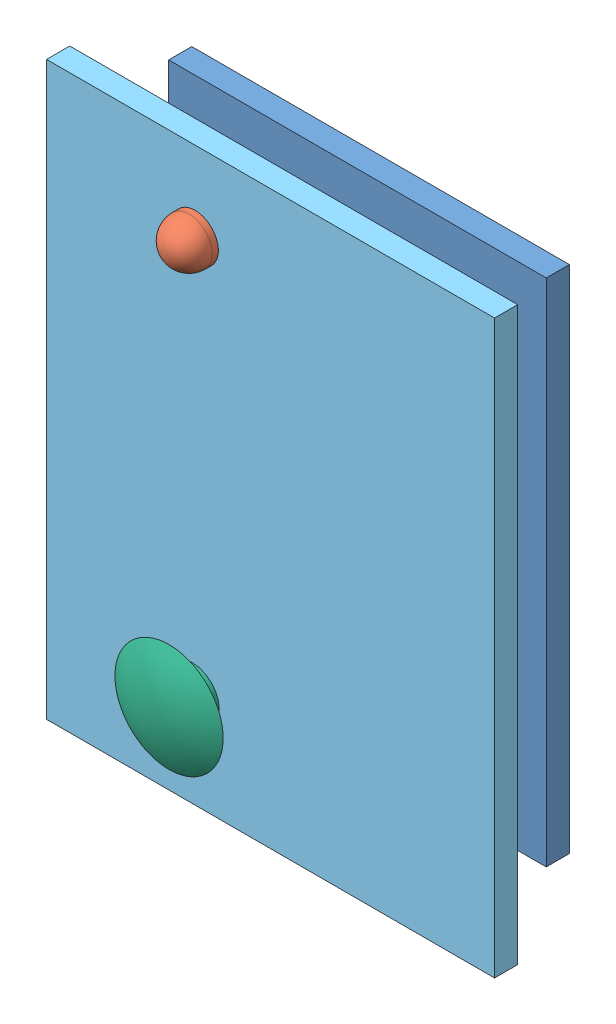
SolidWorks assembly Установка на панель, configuration По умолчанию. Lengths in mm.
Overall size (29 37 10.9).
7 component instances, 6 part files, 11 mates.
Components (placement in the parent):
- Плата-2: Плата [По умолчанию] at (-19.3757 14.8386 11.1863) size (24.45 33.02 1.6)
- Светодиод White-1: Светодиод White [По умолчанию] at (-11.7557 44.6836 15.4863) x (0 0 -1) z (1 0 0) size (15 4 3.6)
- Кнопка-1: Кнопка [По умолчанию] at (-11.9466 18.9926 12.8863) x (1 0 0) z (0 -1 0) size (8 3.1 6.3)
  - B3FS_1000_BASE-1: B3FS_1000_BASE [По умолчанию] at origin size (8 2.6 6.3)
  - B3FS_1000_BUTTON-1: B3FS_1000_BUTTON [По умолчанию] at (0 3 0) x (0.711738 0 -0.702446) z (0.702446 0 0.711738) size (3 0.6 3)
- Панель-1: Панель [По умолчанию] at (-21.3757 12.8386 17.0863) size (29 37 1.5)
- Кнопка-2: Кнопка [По умолчанию] at (1.2262 2.3103 54.0176) x (0 0 1) z (-0.995928 -0.090149 0) size (5 7 7)
Mates (geometry in assembly coordinates):
- Концентричный1: concentric anti-aligned: cylinder of Светодиод White-1 through (-11.7557 44.6836 15.4863) axis (0 0 -1) radius 1.5; cylinder of Панель-1 through (-11.7557 44.6836 17.0863) axis (0 0 1) radius 1.5
- Концентричный3: concentric aligned: cylinder of Панель-1 through (-11.9466 18.9926 17.0863) axis (0 0 1) radius 1.75; circle of Кнопка-2
- Расстояние1: distance = 0.5 mm aligned: plane of Кнопка-2; plane of Панель-1 through (-21.3757 12.8386 18.5863) normal (0 0 1)
- Совпадение5: coincident anti-aligned: plane of Плата-2 through (-19.3757 14.8386 12.7863) normal (0 0 1); plane of Кнопка-1/B3FS_1000_BASE-1 through (-15.1466 20.8926 12.7863) normal (0 0 -1)
- Расстояние4: distance = 0.35 mm aligned: plane of Кнопка-1/B3FS_1000_BASE-1 through (-15.4466 16.3926 13.7863) normal (0 -1 0); plane of Плата-2 through (-16.7468 16.0426 12.7863) normal (0 -1 0)
- Совпадение6: coincident aligned: plane of Плата-2 through (-15.1466 17.4447 12.7863) normal (1 0 0); plane of Кнопка-1/B3FS_1000_BASE-1 through (-15.1466 17.0926 13.4863) normal (1 0 0)
- Параллельность3: parallel aligned: plane of Плата-2 through (-19.3757 47.8586 12.6863) normal (0 1 0); plane of Светодиод White-1 through (-12.7257 44.9336 5.4863) normal (0 1 0)
- Расстояние5: distance = 4.4 mm anti-aligned: plane of Плата-2 through (-19.3757 14.8386 12.6863) normal (0 0 1); plane of Панель-1 through (-21.3757 12.8386 17.0863) normal (0 0 -1)
- Расстояние6: distance = 2.8 mm anti-aligned: plane of Плата-2 through (-19.3757 14.8386 12.6863) normal (0 0 1); plane of Светодиод White-1 through (-11.7557 44.6836 15.4863) normal (0 0 -1)
- Расстояние7: distance = 2 mm aligned: plane of Панель-1 through (-21.3757 12.8386 18.5863) normal (-1 0 0); plane of Плата-2 through (-19.3757 14.8386 12.6863) normal (-1 0 0)
- Расстояние8: distance = 2 mm aligned: plane of Плата-2 through (-19.3757 14.8386 12.6863) normal (0 -1 0); plane of Панель-1 through (-21.3757 12.8386 18.5863) normal (0 -1 0)
